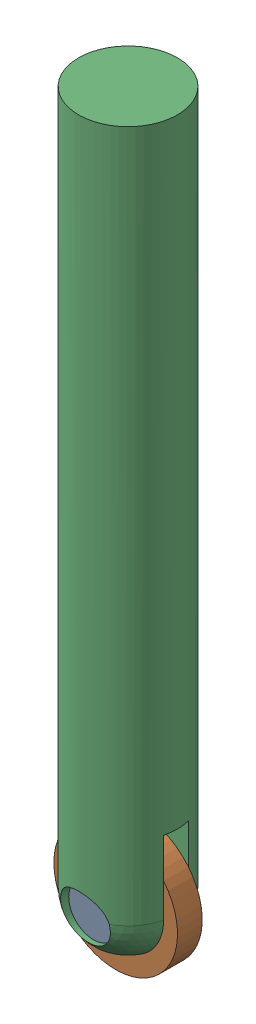
SolidWorks assembly ShaftAssembly, configuration Default. Lengths in mm.
Overall size (32.26 157.13 20).
3 component instances, 3 part files, 4 mates.
Components (placement in the parent):
- PIN-1: PIN [Default] at (-0.1781 -84.926 5.4837) size (10 10 14)
- ROLLER-1: ROLLER [Default] at (32.7107 94.0296 5.4837) x (-0.934655 0.355555 0) z (0 0 1) size (25 25 5)
- SHAFT-1: SHAFT [Default] at (-0.1781 -84.926 5.4837) size (20 149.68 20)
Mates (geometry in assembly coordinates):
- Width1: width aligned: plane of PIN-1 through (-0.1781 7.574 14.9837) normal (0 0 1); plane of ROLLER-1 through (-0.1781 7.574 0.9837) normal (0 0 -1); plane of PIN-1 through (-0.1781 7.574 10.4837) normal (0 0 1); plane of ROLLER-1 through (-0.1781 7.574 5.4837) normal (0 0 -1)
- Width2: width aligned: plane of ROLLER-1 through (-0.1781 7.574 5.4837) normal (0 0 -1); plane of SHAFT-1 through (-0.1781 7.574 10.4837) normal (0 0 1); plane of ROLLER-1 through (-10.1781 23.4746 10.4837) normal (0 0 -1); plane of SHAFT-1 through (-10.1781 23.4746 5.4837) normal (0 0 1)
- Concentric1: concentric aligned: cylinder of PIN-1 through (-0.1781 7.574 14.9837) axis (0 0 -1) radius 5; cylinder of ROLLER-1 through (-0.1781 7.574 10.4837) axis (0 0 -1) radius 5
- Concentric2: concentric anti-aligned: cylinder of PIN-1 through (-0.1781 7.574 14.9837) axis (0 0 -1) radius 5; cylinder of SHAFT-1 through (-0.1781 7.574 -2.0163) axis (0 0 1) radius 5
